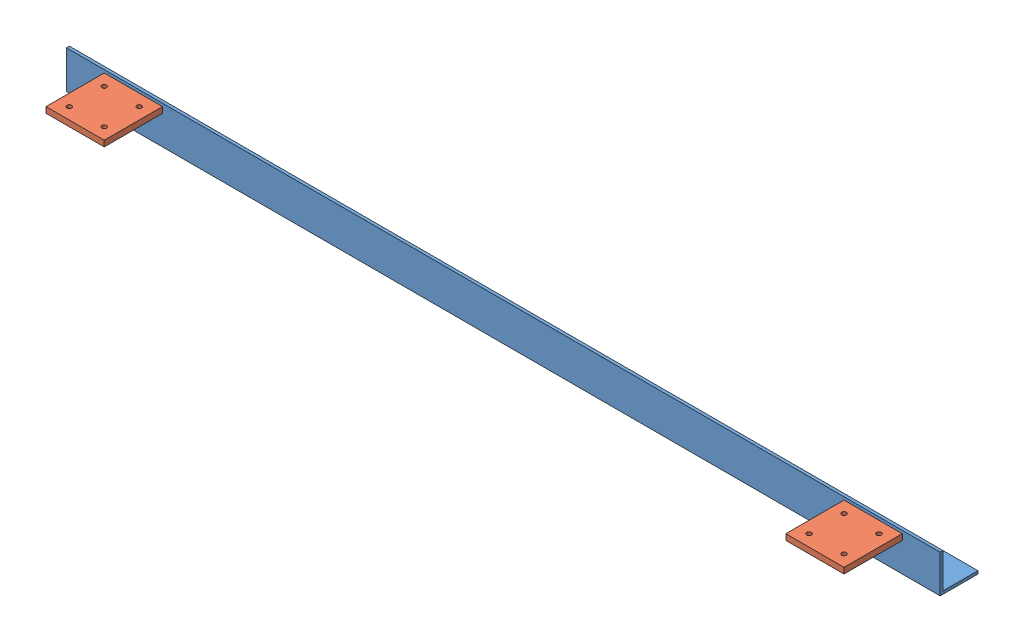
SolidWorks assembly ТЫЛ, configuration По умолчанию. Lengths in mm.
Overall size (1500 65 165).
3 component instances, 2 part files, 6 mates.
Components (placement in the parent):
- СТтыл-2: СТтыл [По умолчанию] at origin size (1500 65 65)
- ПланкаУГл-3: ПланкаУГл [По умолчанию] at (115 50 50) size (100 10 100)
- ПланкаУГл-4: ПланкаУГл [По умолчанию] at (1385 50 50) size (100 10 100)
Mates (geometry in assembly coordinates):
- Совпадение6: coincident anti-aligned: plane of СТтыл-2 through (1500 0 0) normal (0 0 1); plane of ПланкаУГл-3 through (65 30 0) normal (0 0 -1)
- Расстояние3: distance = 65 mm aligned: plane of ПланкаУГл-3 through (65 60 100) normal (-1 0 0); plane of СТтыл-2 through (0 0 0) normal (-1 0 0)
- Расстояние4: distance = 50 mm aligned: plane of ПланкаУГл-3 through (115 50 50) normal (0 -1 0); plane of СТтыл-2 through (1500 0 0) normal (0 -1 0)
- Совпадение9: coincident aligned: plane of ПланкаУГл-3 through (115 20 50) normal (0 -1 0); plane of ПланкаУГл-4 through (1385 20 50) normal (0 -1 0)
- Совпадение10: coincident aligned: plane of ПланкаУГл-3 through (65 30 100) normal (0 0 1); plane of ПланкаУГл-4 through (1335 30 100) normal (0 0 1)
- Расстояние5: distance = 65 mm aligned: plane of СТтыл-2 through (1500 0 0) normal (1 0 0); plane of ПланкаУГл-4 through (1435 60 100) normal (1 0 0)
